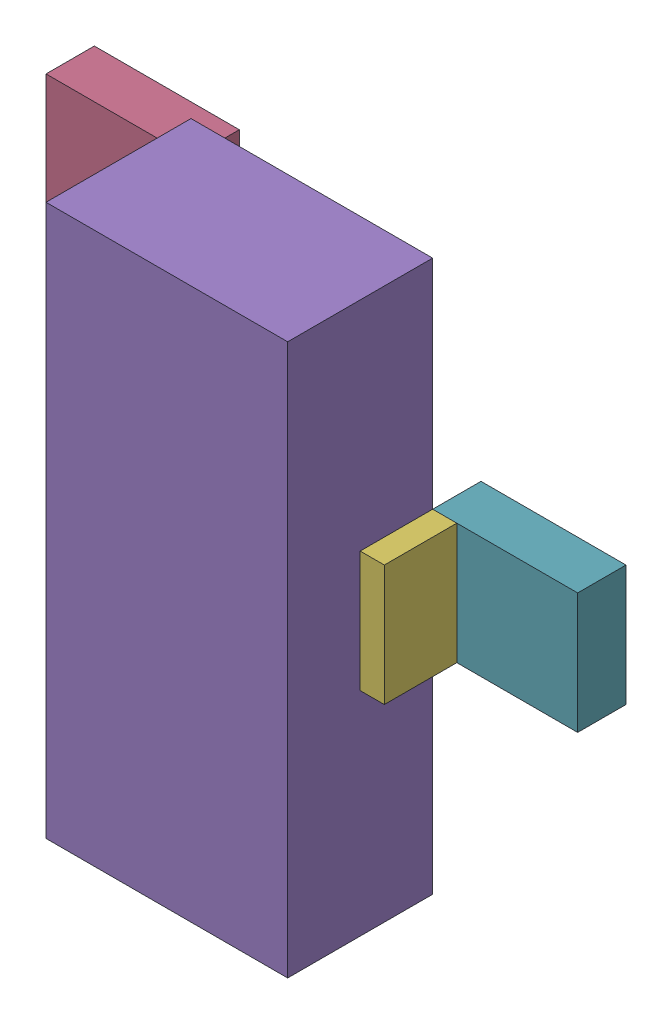
SolidWorks assembly Q8, configuration Default. Lengths in mm.
Overall size (2.79 2.9 1.02).
14 component instances, 3 part files, 0 mates.
Components (placement in the parent):
- 898052632-1: 898052632 [Default] at (39.339 16.3393 0.254) size (0.13 0.64 0.38)
  - Extruded_12-1: Extruded_12 [Default] at origin size (0.13 0.64 0.38)
- 898052496-1: 898052496 [Default] at (39.0215 16.3393 0) size (0.76 0.64 0.25)
  - Extruded_10-1: Extruded_10 [Default] at origin size (0.76 0.64 0.25)
- 898052632-2: 898052632 [Default] at (39.339 18.2443 0.254) size (0.13 0.64 0.38)
  - Extruded_12-1: Extruded_12 [Default] at origin size (0.13 0.64 0.38)
- 898052496-2: 898052496 [Default] at (39.0215 18.2443 0) size (0.76 0.64 0.25)
  - Extruded_10-1: Extruded_10 [Default] at origin size (0.76 0.64 0.25)
- 898052360-1: 898052360 [Default] at (40.0375 17.2918 0.254) size (1.27 2.9 0.76)
  - Extruded_11-1: Extruded_11 [Default] at origin size (1.27 2.9 0.76)
- 898052632-3: 898052632 [Default] at (40.736 17.2791 0.254) size (0.13 0.64 0.38)
  - Extruded_12-1: Extruded_12 [Default] at origin size (0.13 0.64 0.38)
- 898052496-3: 898052496 [Default] at (41.0535 17.2791 0) size (0.76 0.64 0.25)
  - Extruded_10-1: Extruded_10 [Default] at origin size (0.76 0.64 0.25)
